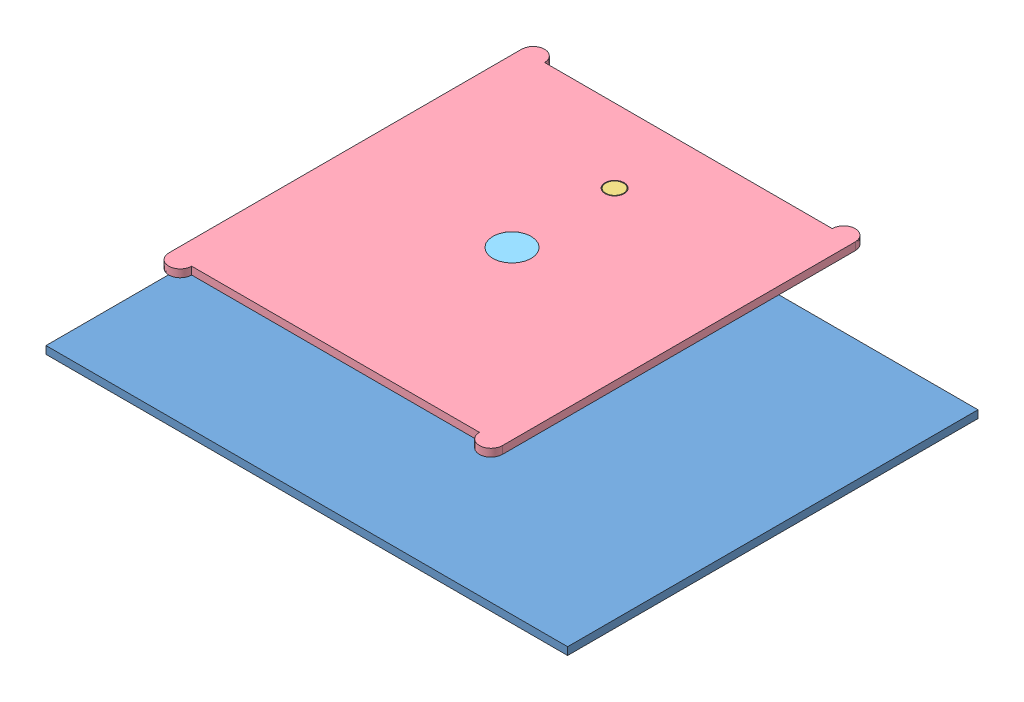
SolidWorks assembly Assembly, configuration Default. Lengths in mm.
Overall size (680 311.05 535).
5 component instances, 5 part files, 12 mates.
Components (placement in the parent):
- Base Plate 535 x 680 mm-1: Base Plate 535 x 680 mm [Default] at (242.1652 314.3002 552.2709) size (680 10 535)
- Air Cylynder Body 100 x 150-1: Air Cylynder Body 100 x 150 [Default] at (242.1652 160.3002 552.2709) size (200 154 220)
- Guider Pin 25 x 200-1: Guider Pin 25 x 200 [Default] at (242.1652 271.3475 418.5209) size (25 200 25)
- Plate#1-1: Plate#1 [Default] at (242.1652 471.3475 552.2709) size (435 10 490)
- Shaft 50mm-1: Shaft 50mm [Default] at (242.1652 289.3475 552.2709) size (186 182 186)
Mates (geometry in assembly coordinates):
- Concentric1: concentric: circle of assembly; circle of assembly; circle of Base Plate 535 x 680 mm-1; circle of Air Cylynder Body 100 x 150-1
- Coincident2: coincident: plane of assembly; plane of assembly; plane of Base Plate 535 x 680 mm-1 through (242.1652 314.3002 552.2709) normal (0 -1 0); plane of Air Cylynder Body 100 x 150-1 through (332.1652 314.3002 652.2709) normal (0 1 0)
- Parallel1: parallel: plane of assembly; plane of assembly; plane of Base Plate 535 x 680 mm-1 through (-97.8348 324.3002 819.7709) normal (0 0 1); plane of Air Cylynder Body 100 x 150-1 through (162.1652 314.3002 652.2709) normal (0 0 1)
- Concentric2: concentric: circle of assembly; circle of assembly; circle of Base Plate 535 x 680 mm-1; circle of Plate#1-1
- Parallel2: parallel: plane of assembly; plane of assembly; plane of Base Plate 535 x 680 mm-1 through (582.1652 324.3002 284.7709) normal (1 0 0); plane of Plate#1-1 through (459.6652 461.3475 322.2709) normal (1 0 0)
- Concentric3: concentric: circle of assembly; circle of assembly; circle of Guider Pin 25 x 200-1; circle of Plate#1-1
- Coincident8: coincident: plane of assembly; plane of assembly; plane of Guider Pin 25 x 200-1 through (242.1652 471.3475 418.5209) normal (0 1 0); plane of Plate#1-1 through (444.6652 471.3475 782.2709) normal (0 1 0)
- Concentric4: concentric: circle of assembly; circle of assembly; circle of Base Plate 535 x 680 mm-1; circle of Shaft 50mm-1
- Parallel3: parallel: plane of assembly; plane of assembly; plane of Base Plate 535 x 680 mm-1 through (-97.8348 324.3002 819.7709) normal (0 0 1); plane of Shaft 50mm-1 through (149.1652 291.3475 645.2709) normal (0 0 1)
- LimitDistance1: limit distance = 129.0473 mm: plane of assembly; plane of assembly; plane of Shaft 50mm-1 through (242.1652 289.3475 552.2709) normal (0 -1 0); plane of Air Cylynder Body 100 x 150-1 through (332.1652 160.3002 652.2709) normal (0 -1 0)
- Concentric5: concentric: circle of assembly; circle of assembly; circle of Plate#1-1; circle of Shaft 50mm-1
- Coincident13: coincident: plane of assembly; plane of assembly; plane of Plate#1-1 through (444.6652 471.3475 782.2709) normal (0 1 0); plane of Shaft 50mm-1 through (242.1652 471.3475 552.2709) normal (0 1 0)
